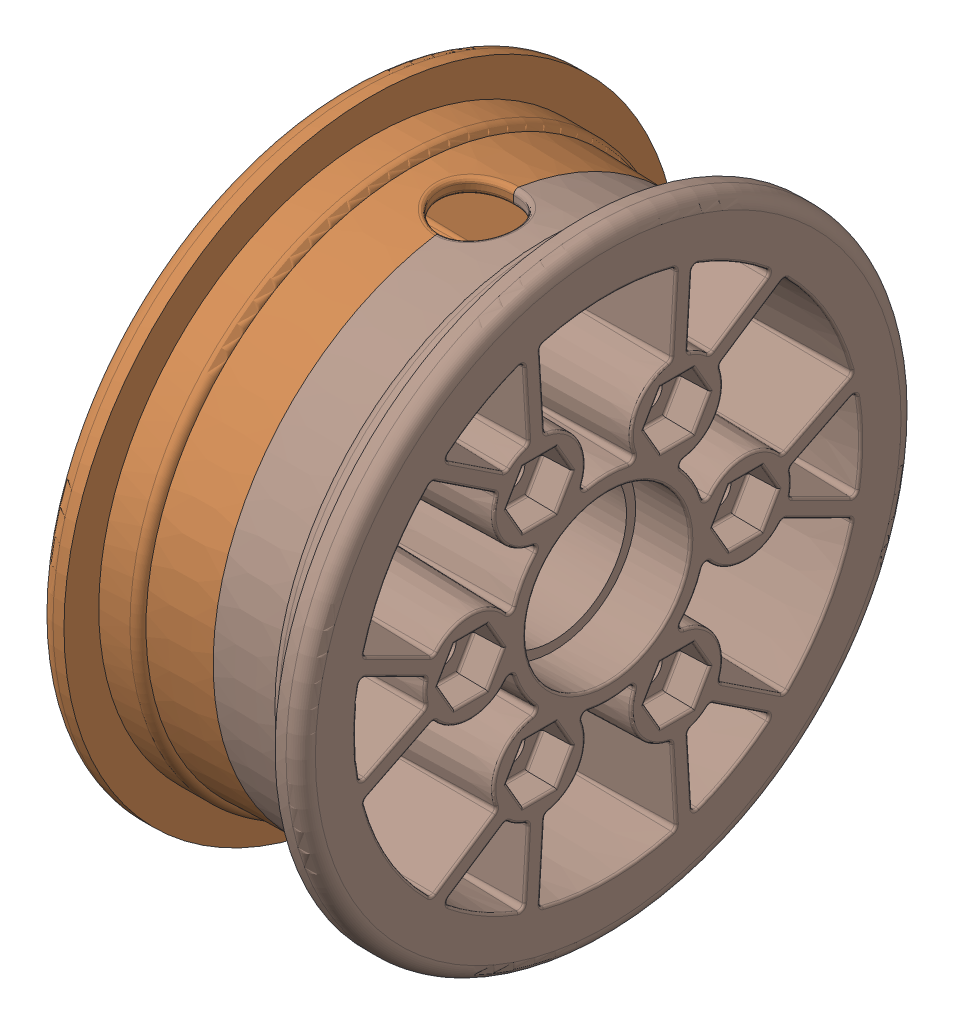
SolidWorks assembly Pneumatic Hub, configuration Default. Lengths in mm.
Overall size (45.47 106.55 106.55).
8 component instances, 2 part files, 0 mates.
Components (placement in the parent):
- #4x1.00, Plastic Thread Rolling Screw, Pan Head, Cross Recessed, Zinc Plated (Plastic Applications)_-1: #4x1.00, Plastic Thread Rolling Screw, Pan Head, Cross Recessed, Zinc Plated (Plastic Applications)_ [Default] at (7.3269 34.0601 29.3991) x (-1 0 0) z (0 -0.924225 -0.381849) size (27.43 5.56 5.56)
- Hub-1: Hub [Default] at (-28.6141 -1.1351 9.0791) size (25.79 106.55 106.55)
- #4x1.00, Plastic Thread Rolling Screw, Pan Head, Cross Recessed, Zinc Plated (Plastic Applications)_-2: #4x1.00, Plastic Thread Rolling Screw, Pan Head, Cross Recessed, Zinc Plated (Plastic Applications)_ [Default] at (7.3269 -1.1351 -31.5609) x (-1 0 0) z (0 0.131421 0.991327) size (27.43 5.56 5.56)
- #4x1.00, Plastic Thread Rolling Screw, Pan Head, Cross Recessed, Zinc Plated (Plastic Applications)_-3: #4x1.00, Plastic Thread Rolling Screw, Pan Head, Cross Recessed, Zinc Plated (Plastic Applications)_ [Default] at (-19.0891 -1.1351 49.7191) x (1 0 0) z (0 -0.750107 0.661316) size (27.43 5.56 5.56)
- #4x1.00, Plastic Thread Rolling Screw, Pan Head, Cross Recessed, Zinc Plated (Plastic Applications)_-4: #4x1.00, Plastic Thread Rolling Screw, Pan Head, Cross Recessed, Zinc Plated (Plastic Applications)_ [Default] at (7.3269 -36.3304 29.3991) x (-1 0 0) z (0 0.792804 -0.609477) size (27.43 5.56 5.56)
- #4x1.00, Plastic Thread Rolling Screw, Pan Head, Cross Recessed, Zinc Plated (Plastic Applications)_-5: #4x1.00, Plastic Thread Rolling Screw, Pan Head, Cross Recessed, Zinc Plated (Plastic Applications)_ [Default] at (-19.0891 34.0601 -11.2409) x (1 0 0) z (0 0.94777 0.318954) size (27.43 5.56 5.56)
- #4x1.00, Plastic Thread Rolling Screw, Pan Head, Cross Recessed, Zinc Plated (Plastic Applications)_-6: #4x1.00, Plastic Thread Rolling Screw, Pan Head, Cross Recessed, Zinc Plated (Plastic Applications)_ [Default] at (-19.0891 -36.3304 -11.2409) x (1 0 0) z (0 -0.197663 -0.98027) size (27.43 5.56 5.56)
- Hub-2: Hub [Default] at (16.8519 -1.1351 9.0791) x (-1 0 0) z (0 0 -1) size (25.79 106.55 106.55)
